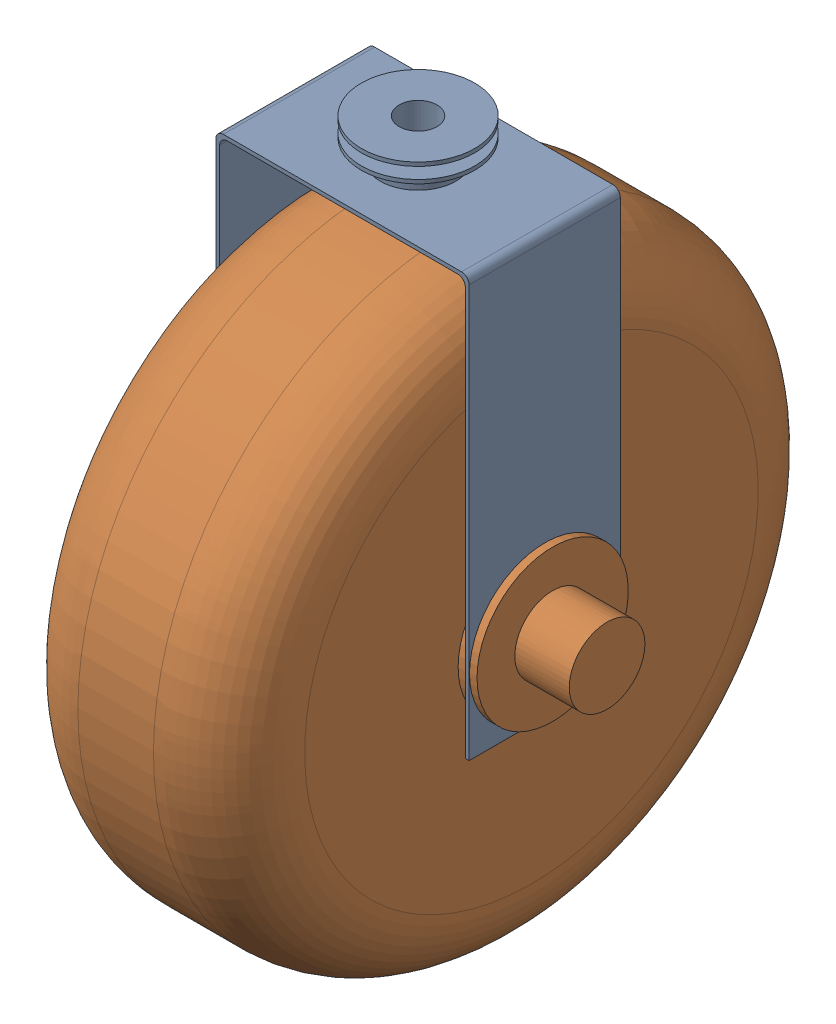
SolidWorks assembly Wheel Assembly 2, configuration Default. Lengths in mm.
Overall size (127 239.3 222.05).
2 component instances, 2 part files, 2 mates.
Components (placement in the parent):
- Wheel Housing 2-1: Wheel Housing 2 [Default] at (-25.9605 -20.5145 45.2641) size (85.09 153.67 50.8)
- Wheel-1: Wheel [Default] at (-25.9605 -20.5145 70.6641) x (0 0.097537 0.995232) z (0 -0.995232 0.097537) size (203.2 127 203.2)
Mates (geometry in assembly coordinates):
- Width3: width anti-aligned: plane of Wheel-1 through (-64.0605 -20.5145 70.6641) normal (-1 0 0); plane of Wheel Housing 2-1 through (12.1395 -20.5145 70.6641) normal (1 0 0); plane of Wheel-1 through (16.5845 92.5155 96.0641) normal (1 0 0); plane of Wheel Housing 2-1 through (-68.5055 92.5155 96.0641) normal (-1 0 0)
- Concentric1: concentric aligned: cylinder of Wheel Housing 2-1 through (16.5845 -20.5145 70.6641) axis (-1 0 0) radius 12.7; cylinder of Wheel-1 through (37.5395 -20.5145 70.6641) axis (-1 0 0) radius 12.7
